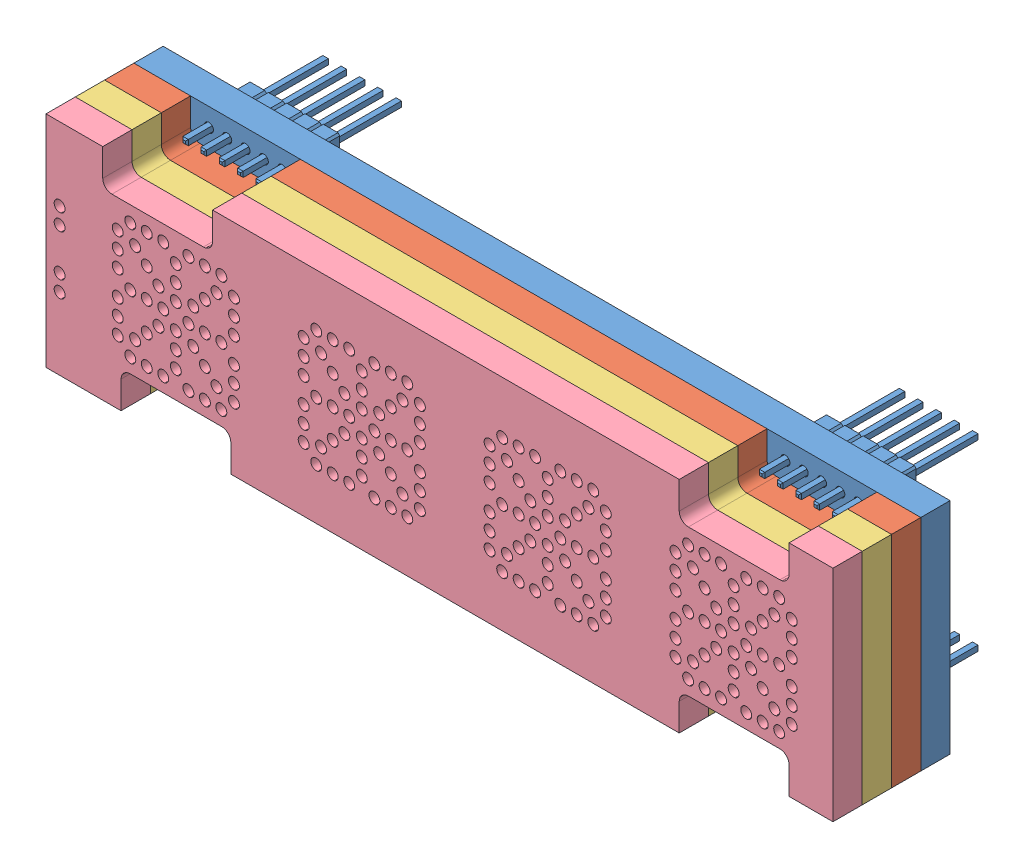
SolidWorks assembly ufc_v4_opt_disp, configuration Default. Lengths in mm.
Overall size (43 12 11.25).
4 component instances, 4 part files, 10 mates.
Components (placement in the parent):
- ufc_v4_opt-1: ufc_v4_opt [Default] at origin size (43 12 7.8)
- ufc_v4_opt_layer2-1: ufc_v4_opt_layer2 [Default] at (0 0 1.6) size (43 12 1.6)
- ufc_v4_opt_layer3-1: ufc_v4_opt_layer3 [Default] at (0 0 3.2) size (43 12 1.6)
- ufc_v4_opt_layer4-1: ufc_v4_opt_layer4 [Default] at (0 0 4.8) size (43 12 1.6)
Mates (geometry in assembly coordinates):
- Coincident1: coordinate: point of ufc_v4_opt-1
- Coincident3: coincident anti-aligned: plane of ufc_v4_opt_layer2-1 through (0.0686 0 3.2) normal (0 0 1); plane of ufc_v4_opt_layer3-1 through (0.0686 0 3.2) normal (0 0 -1)
- Coincident4: coincident anti-aligned: plane of ufc_v4_opt_layer3-1 through (0.0686 0 4.8) normal (0 0 1); plane of ufc_v4_opt_layer4-1 through (0.0686 0 4.8) normal (0 0 -1)
- Coincident5: coincident anti-aligned: plane of ufc_v4_opt-1 through (0 0 1.6) normal (0 0 1); plane of ufc_v4_opt_layer2-1 through (0.0686 0 1.6) normal (0 0 -1)
- Coincident6: coincident aligned: plane of ufc_v4_opt-1 through (21.5 6 0) normal (0 1 0); plane of ufc_v4_opt_layer2-1 through (13.1 6 1.6) normal (0 1 0)
- Coincident7: coincident aligned: plane of ufc_v4_opt-1 through (21.5 6 0) normal (0 1 0); plane of ufc_v4_opt_layer3-1 through (13.1 6 3.2) normal (0 1 0)
- Coincident8: coincident aligned: plane of ufc_v4_opt-1 through (21.5 6 0) normal (0 1 0); plane of ufc_v4_opt_layer4-1 through (13.1 6 4.8) normal (0 1 0)
- Coincident9: coincident aligned: plane of ufc_v4_opt-1 through (21.5 -6 0) normal (1 0 0); plane of ufc_v4_opt_layer2-1 through (21.5 -6 1.6) normal (1 0 0)
- Coincident10: coincident aligned: plane of ufc_v4_opt-1 through (21.5 -6 0) normal (1 0 0); plane of ufc_v4_opt_layer3-1 through (21.5 -6 3.2) normal (1 0 0)
- Coincident11: coincident aligned: plane of ufc_v4_opt-1 through (21.5 -6 0) normal (1 0 0); plane of ufc_v4_opt_layer4-1 through (21.5 -6 4.8) normal (1 0 0)
